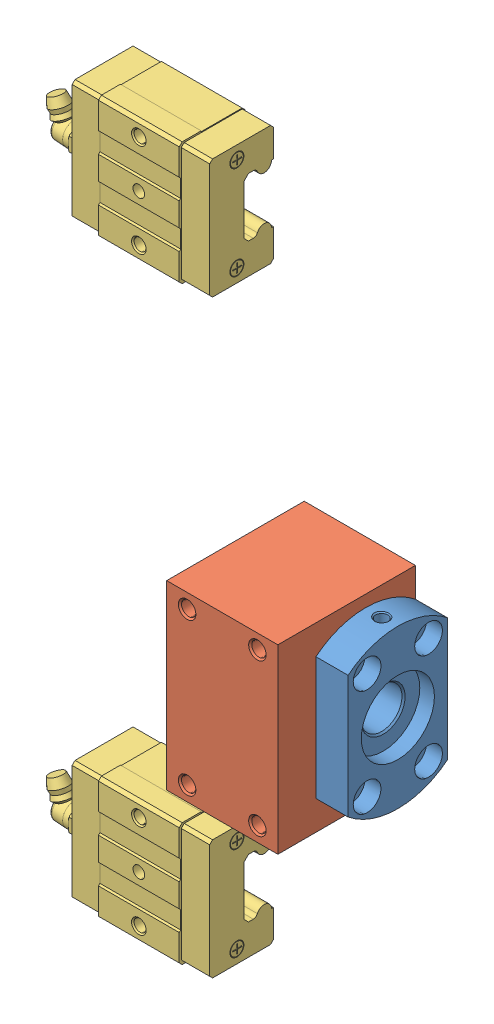
SolidWorks assembly Schlitten_x-Achse, configuration Standard. Lengths in mm.
Overall size (95 243.5 47).
4 component instances, 3 part files, 9 mates.
Components (placement in the parent):
- x.2-1: x.2 [Standard] at (-748.6092 -2.4171 54) size (48 54 34)
- bnfb1510c_30_2_14b-1: bnfb1510c_30_2_14b [Standard] at (-13.1092 -2.4171 54) x (0 1 0) z (1 0 0) size (62 47 38)
- x.2.1.1.1-1: x.2.1.1.1 [Standard] at (-41.6092 139.0829 56) x (0 -1 0) z (-1 0 0) size (42 22.5 60)
- x.2.1.1.1-2: x.2.1.1.1 [Standard] at (-41.6092 -62.4171 56) x (0 -1 0) z (-1 0 0) size (42 22.5 60)
Mates (geometry in assembly coordinates):
- Abstand3: distance = 33 mm aligned: plane of bnfb1510c_30_2_14b-1 through (-32.1092 -2.4171 54) normal (-1 0 0); plane of x.2.1.1.1-2 through (-65.1092 -62.4171 61.5) normal (-1 0 0)
- Abstand1: distance = 89.5 mm anti-aligned: plane of x.2.1.1.1-1 through (-55.4092 118.0829 76.5) normal (0 -1 0); plane of bnfb1510c_30_2_14b-1 through (5.8908 28.5829 37) normal (0 1 0)
- Abstand2: distance = 8 mm anti-aligned: plane of x.2.1.1.1-2 through (-55.4092 -41.4171 83) normal (0 1 0); plane of bnfb1510c_30_2_14b-1 through (5.8908 -33.4171 84) normal (0 -1 0)
- Konzentrisch2: concentric aligned: cylinder of x.2-1 through (-12.3592 -2.4171 54) axis (1 0 0) radius 15.5; cylinder of bnfb1510c_30_2_14b-1 through (5.8908 -2.4171 54) axis (1 0 0) radius 15.7
- Deckungsgleich10: coincident anti-aligned: plane of x.2-1 through (5.8908 -2.4171 54) normal (-1 0 0); plane of bnfb1510c_30_2_14b-1 through (5.8908 -2.4171 54) normal (1 0 0)
- Parallel1: parallel aligned: plane of x.2-1 through (5.8908 -23.3933 71) normal (0 0 1); plane of bnfb1510c_30_2_14b-1 through (5.8908 28.5829 84) normal (0 0 1)
- Deckungsgleich12: coincident aligned: plane of bnfb1510c_30_2_14b-1 through (5.8908 28.5829 84) normal (0 0 1); plane of x.2.1.1.1-2 through (-65.4092 -51.4171 84) normal (0 0 1)
- Deckungsgleich13: coincident aligned: plane of bnfb1510c_30_2_14b-1 through (5.8908 28.5829 84) normal (0 0 1); plane of x.2.1.1.1-1 through (-65.4092 135.0829 84) normal (0 0 1)
- Deckungsgleich14: coincident aligned: plane of x.2.1.1.1-1 through (-75.1092 139.0829 61.5) normal (-1 0 0); plane of x.2.1.1.1-2 through (-75.1092 -62.4171 61.5) normal (-1 0 0)
